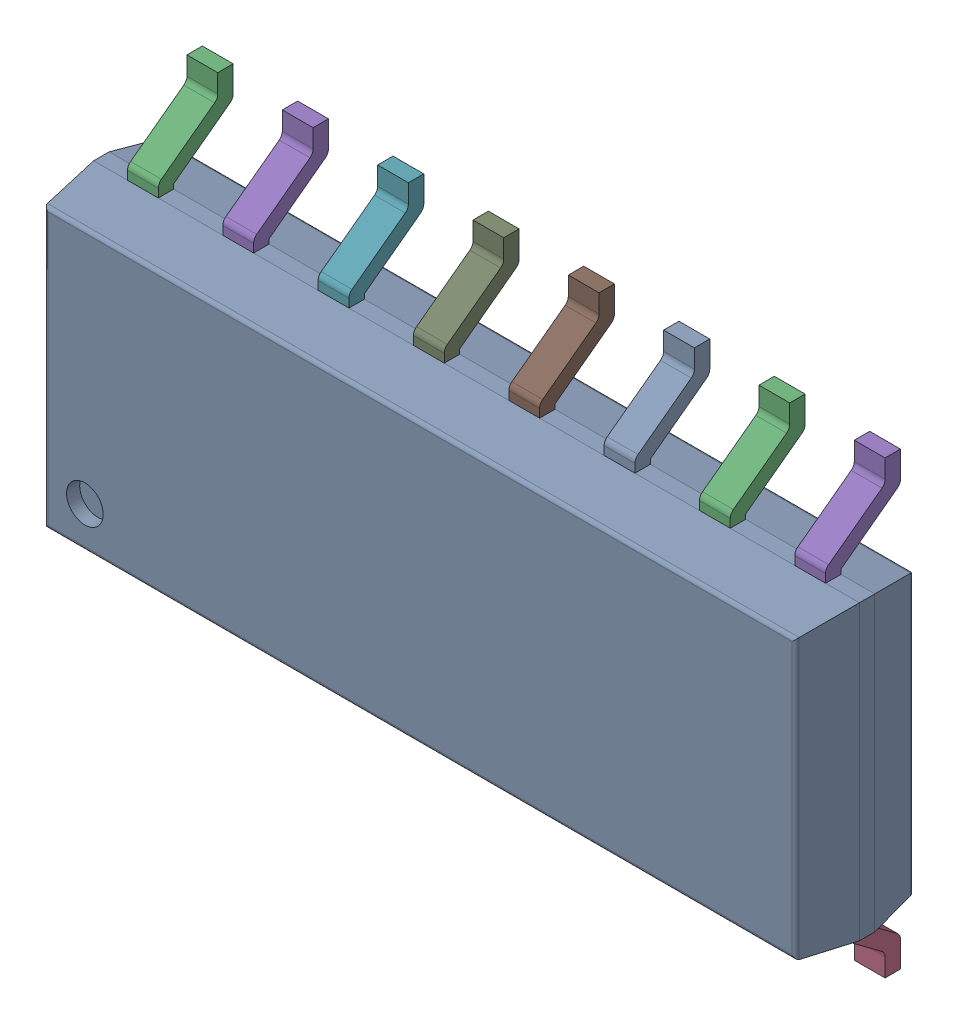
SolidWorks assembly IC15_1.step, configuration Default. Lengths in mm.
Overall size (10.2 6 1.75).
3 component instances, 2 part files, 0 mates.
Components (placement in the parent):
- 6348803008_1.step-3: 6348803008_1.step [Default] at (520.065 281.09 0) x (0 1 0) z (0 0 1) size (6 10.2 1.75)
  - Body-14_1.step-8: Body-14_1.step [Default] at origin size (3.9 10.2 1.57)
  - PinsArrayLR-15_1.step-8: PinsArrayLR-15_1.step [Default] at origin size (6 9.3 1)
